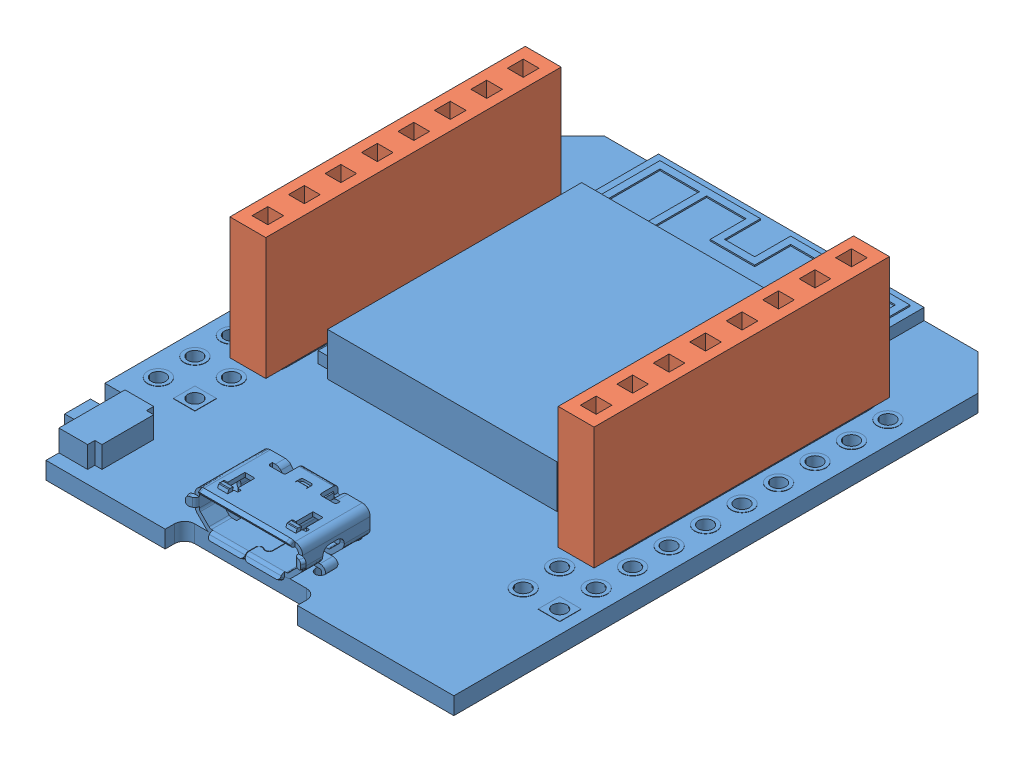
SolidWorks assembly MH-ET Live ESP32 MiniKIT - headers f, configuration Default. Lengths in mm.
Overall size (31 11.5 39).
3 component instances, 2 part files, 9 mates.
Components (placement in the parent):
- MH-ET Live ESP32 MiniKIT-1: MH-ET Live ESP32 MiniKIT [Default] at (137.257 -40.9796 -63.0415) size (31 4.22 39)
- header_f8-1: header_f8 [Default] at (11.43 1.2 -33.155) x (0 0 1) z (-1 0 0) size (20.57 11.5 2.5)
- header_f8-2: header_f8 [Default] at (-11.43 1.2 -33.155) x (0 0 1) z (-1 0 0) size (20.57 11.5 2.5)
Mates (geometry in assembly coordinates):
- Coincident4: coincident aligned: plane of Wemos-Mini-D1-ESP32-1 through (137.257 -40.9796 0) normal (0 0 1)
- Coincident5: coincident aligned: plane of Wemos-Mini-D1-ESP32-1 through (137.257 0 -63.0415) normal (0 1 0)
- Coincident6: coincident aligned: plane of Wemos-Mini-D1-ESP32-1 through (0 -40.9796 -63.0415) normal (1 0 0)
- Coincident7: coincident anti-aligned: plane of Wemos-Mini-D1-ESP32-1 through (-14.1 1.2 -5.5) normal (0 1 0); plane of header_f8-1 through (10.18 1.2 -33.155) normal (0 -1 0)
- Coincident8: coincident anti-aligned: plane of Wemos-Mini-D1-ESP32-1 through (-14.1 1.2 -5.5) normal (0 1 0); plane of header_f8-2 through (-12.68 1.2 -33.155) normal (0 -1 0)
- Coincident9: coincident anti-aligned: line of Wemos-Mini-D1-ESP32-1 through (11.43 -0.02 -31.76) axis (0 1 0); line of header_f8-1 through (11.43 1.2 -31.76) axis (0 -1 0)
- Coincident10: coincident anti-aligned: line of Wemos-Mini-D1-ESP32-1 through (-11.43 -0.0395 -31.76) axis (0 1 0); line of header_f8-2 through (-11.43 1.2 -31.76) axis (0 -1 0)
- Parallel2: parallel anti-aligned: plane of Wemos-Mini-D1-ESP32-1 through (0 -40.9796 -63.0415) normal (1 0 0); plane of header_f8-2 through (-11.43 1.2 -33.155) normal (-1 0 0)
- Parallel3: parallel anti-aligned: plane of Wemos-Mini-D1-ESP32-1 through (0 -40.9796 -63.0415) normal (1 0 0); plane of header_f8-1 through (11.43 1.2 -33.155) normal (-1 0 0)
